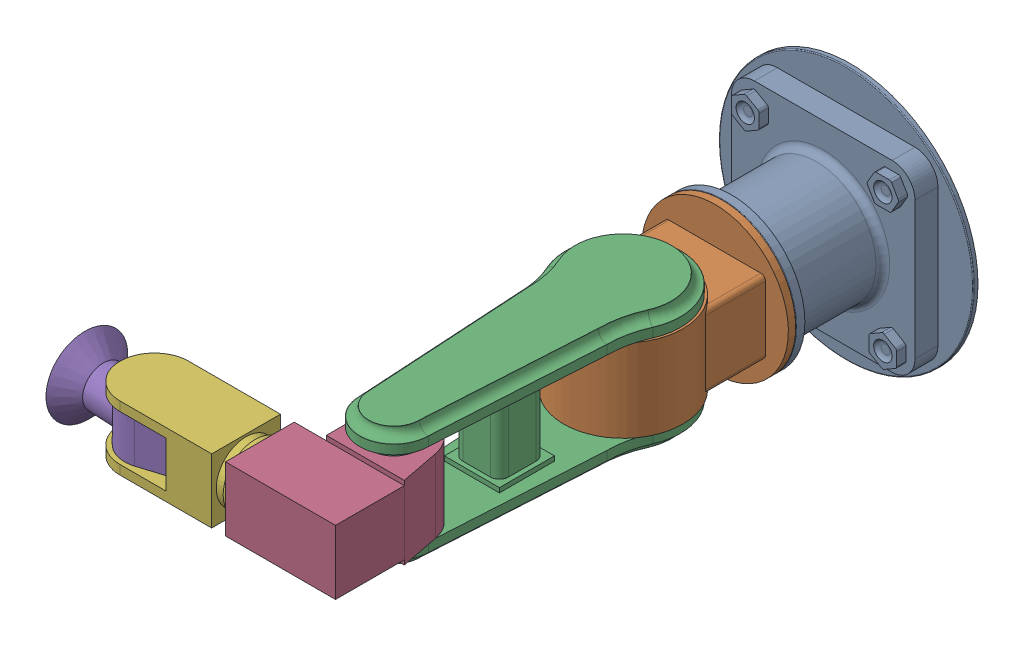
SolidWorks assembly arm, configuration Default. Lengths in mm.
Overall size (813.91 555 1218.33).
5 component instances, 5 part files, 12 mates.
Components (placement in the parent):
- base-2: base [Default] at (428.9988 445.963 66.1485) x (0 1 0) z (1 0 0) size (555 280 555)
- 2-2: 2 [Default] at (428.9988 445.963 226.1485) x (1 0 0) z (0 -1 0) size (320 466 320)
- 3-2: 3 [Default] at (428.9988 445.963 562.1485) x (1 0 0) z (0 0 -1) size (250 260.14 700)
- P1-2: P1 [Default] at (521.5559 435.963 1207.1485) x (-1 0 0) z (0 1 0) size (240 297.5 160)
- gancho-2: gancho [Default] at (139.8006 140.0596 991.4443) x (-1 0 0) z (0 1 0) size (438.97 169.8 170)
Mates (geometry in assembly coordinates):
- Concentric1: concentric anti-aligned: cylinder of base-2 through (428.9988 445.963 146.1485) axis (0 0 1) radius 100; cylinder of 2-2 through (428.9988 445.963 346.1485) axis (0 0 -1) radius 100
- Coincident1: coincident anti-aligned: plane of base-2 through (428.9988 445.963 346.1485) normal (0 0 1); plane of 2-2 through (428.9988 445.963 346.1485) normal (0 0 -1)
- Concentric2: concentric aligned: cylinder of 2-2 through (428.9988 355.963 562.1485) axis (0 1 0) radius 75; cylinder of 3-2 through (428.9988 355.963 562.1485) axis (0 1 0) radius 75
- Coincident2: coincident anti-aligned: plane of 2-2 through (428.9988 355.963 562.1485) normal (0 -1 0); plane of 3-2 through (428.9988 355.963 562.1485) normal (0 1 0)
- Concentric3: concentric anti-aligned: cylinder of 3-2 through (428.9988 355.963 1062.1485) axis (0 1 0) radius 50; cylinder of P1-2 through (428.9988 515.963 1062.1485) axis (0 -1 0) radius 50
- Coincident3: coincident anti-aligned: plane of 3-2 through (428.9988 355.963 562.1485) normal (0 1 0); plane of P1-2 through (428.9988 355.963 1062.1485) normal (0 -1 0)
- Concentric4: concentric anti-aligned: cylinder of P1-2 through (361.5559 435.963 1207.1485) axis (-1 0 0) radius 65; cylinder of gancho-2 through (281.5559 435.963 1207.1485) axis (1 0 0) radius 65
- Coincident4: coincident anti-aligned: plane of P1-2 through (281.5559 365.963 1282.1485) normal (-1 0 0); plane of gancho-2 through (281.5559 435.963 1207.1485) normal (1 0 0)
- Parallel1: parallel aligned: plane of base-2 through (628.9988 245.963 126.1485) normal (0 -1 0); plane of 3-2 through (428.9988 315.963 1062.1485) normal (0 -1 0)
- Coincident7: coincident aligned: plane of P1-2 through (281.5559 365.963 1282.1485) normal (0 -1 0); plane of gancho-2 through (51.5559 365.963 1207.1485) normal (0 -1 0)
- Parallel3: parallel anti-aligned: plane of base-2 through (428.9988 445.963 76.1485) normal (0 0 1); plane of gancho-2 through (251.5559 505.963 1132.1485) normal (0 0 -1)
- Parallel5: parallel aligned: plane of base-2 through (428.9988 445.963 66.1485) normal (0 0 -1); plane of 3-2 through (448.7522 325.963 574.2634) normal (0 0 -1)
